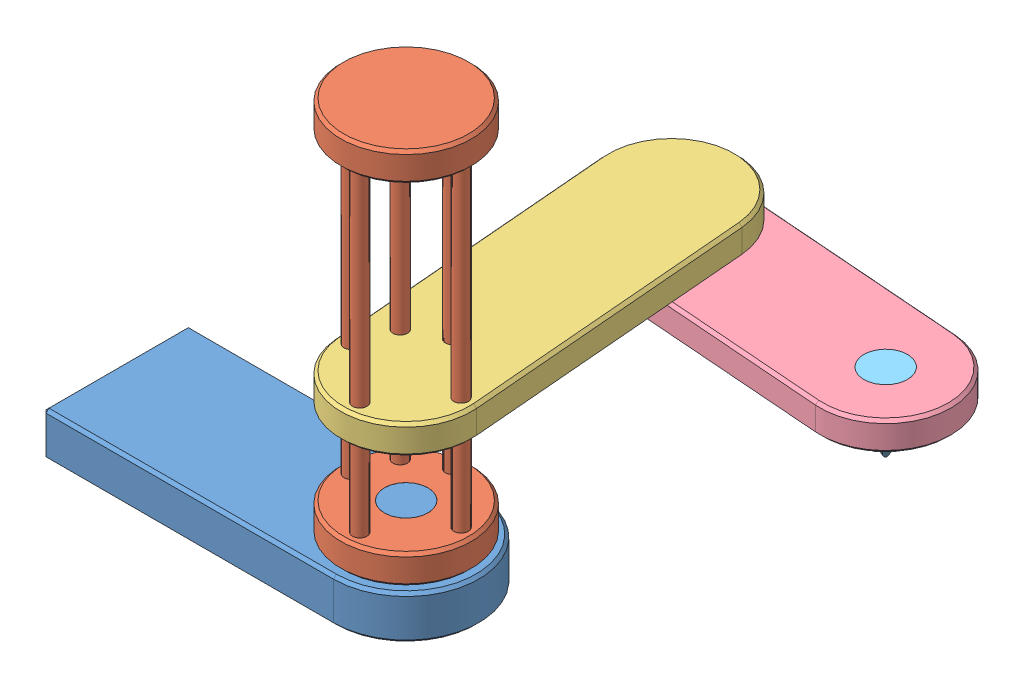
SolidWorks assembly Assem1, configuration Default. Lengths in mm.
Overall size (391.24 290 297.89).
5 component instances, 5 part files, 9 mates.
Components (placement in the parent):
- Part1-1: Part1 [Default] at (86.7431 101.8858 214.7814) size (250 50 100)
- Part2-1: Part2 [Default] at (186.7431 131.8858 214.7814) x (-0.08291 0 -0.996557) z (0.996557 0 -0.08291) size (90 260 90)
- Part3-1: Part3 [Default] at (178.4521 209.3131 115.1257) x (-0.08291 0 -0.996557) z (0.996557 0 -0.08291) size (290 40 90)
- Part4-1: Part4 [Default] at (249.931 189.3131 21.5338) x (0.997123 0 0.075798) z (-0.075798 0 0.997123) size (250 20 90)
- Part5-1: Part5 [Default] at (329.7009 189.3131 27.5976) size (48.4 50 48.4)
Mates (geometry in assembly coordinates):
- Concentric1: concentric anti-aligned: cylinder of Part1-1 through (186.7431 151.8858 214.7814) axis (0 -1 0) radius 15; cylinder of Part2-1 through (186.7431 131.8858 214.7814) axis (0 1 0) radius 15
- Coincident1: coincident anti-aligned: plane of Part1-1 through (186.7431 131.8858 214.7814) normal (0 1 0); plane of Part2-1 through (186.7431 131.8858 214.7814) normal (0 -1 0)
- Concentric2: concentric anti-aligned: cylinder of Part2-1 through (160.0277 371.8858 192.1698) axis (0 -1 0) radius 5; cylinder of Part3-1 through (160.0277 209.3131 192.1698) axis (0 1 0) radius 5
- Concentric3: concentric anti-aligned: cylinder of Part2-1 through (189.6449 371.8858 249.6609) axis (0 -1 0) radius 5; cylinder of Part3-1 through (189.6449 209.3131 249.6609) axis (0 1 0) radius 5
- LimitDistance1: limit distance = 57.4274 mm anti-aligned: plane of Part3-1 through (186.7431 209.3131 214.7814) normal (0 -1 0); plane of Part2-1 through (186.7431 151.8858 214.7814) normal (0 1 0)
- Concentric4: concentric aligned: cylinder of Part3-1 through (170.1611 189.3131 15.47) axis (0 1 0) radius 15; cylinder of Part4-1 through (170.1611 189.3131 15.47) axis (0 1 0) radius 15
- Coincident3: coincident anti-aligned: plane of Part3-1 through (186.7431 209.3131 214.7814) normal (0 -1 0); plane of Part4-1 through (170.1611 209.3131 15.47) normal (0 1 0)
- Concentric5: concentric anti-aligned: cylinder of Part4-1 through (329.7009 189.3131 27.5976) axis (0 1 0) radius 15; cylinder of Part5-1 through (329.7009 209.3131 27.5976) axis (0 -1 0) radius 15
- Coincident4: coincident anti-aligned: plane of Part4-1 through (170.1611 189.3131 15.47) normal (0 -1 0); plane of Part5-1 through (329.7009 189.3131 27.5976) normal (0 1 0)
